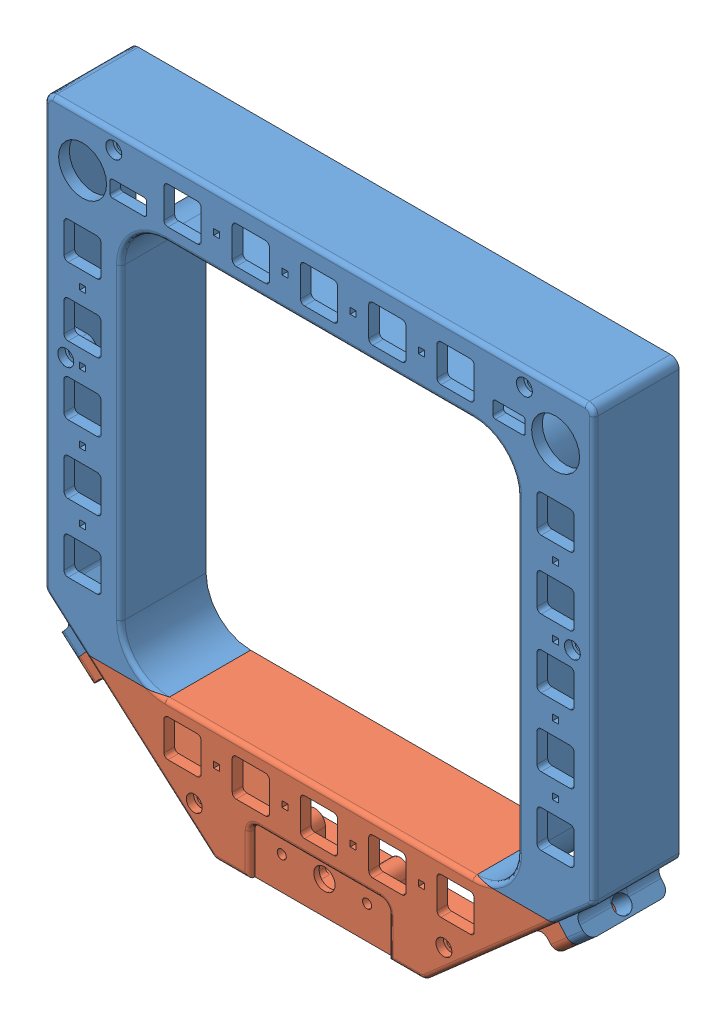
SolidWorks assembly Assem1, configuration Default. Lengths in mm.
Overall size (163.51 172.72 26.39).
2 component instances, 2 part files, 4 mates.
Components (placement in the parent):
- DDI_BTTM_JK-1: DDI_BTTM_JK [Default - Large Rotary] at (43.2005 167.1663 142.4379) size (163.51 143.52 26.39)
- DDI_TOP_JK-2: DDI_TOP_JK [Default - Large Rotary] at (43.2005 167.1663 142.4379) size (148.3 33.97 26.39)
Mates (geometry in assembly coordinates):
- Width1: width: plane of DDI_TOP_JK-2 through (-30.952 20.4719 106.1031) normal (-0.75148 0.659756 0); plane of DDI_BTTM_JK-1 through (117.353 20.4719 81.9731) normal (0.75148 0.659756 0); plane of DDI_TOP_JK-2 through (-30.952 20.4719 141.1679) normal (0.75148 -0.659756 0); plane of DDI_BTTM_JK-1 through (117.353 20.4719 117.0379) normal (-0.75148 -0.659756 0)
- Coincident2: coincident: plane of DDI_BTTM_JK-1 through (43.2005 25.2438 142.4379) normal (0 -1 0); plane of DDI_TOP_JK-2 through (43.2005 25.2438 107.3731) normal (0 1 0)
- Coincident3: coincident: plane of DDI_BTTM_JK-1 through (117.353 20.4719 117.0379) normal (-0.75148 -0.659756 0); plane of DDI_TOP_JK-2 through (117.353 20.4719 81.9731) normal (0.75148 0.659756 0)
- Coincident6: coincident aligned: plane of DDI_BTTM_JK-1 through (43.2005 167.1663 142.4379) normal (0 0 1); plane of DDI_TOP_JK-2 through (43.2005 167.1663 142.4379) normal (0 0 1)
